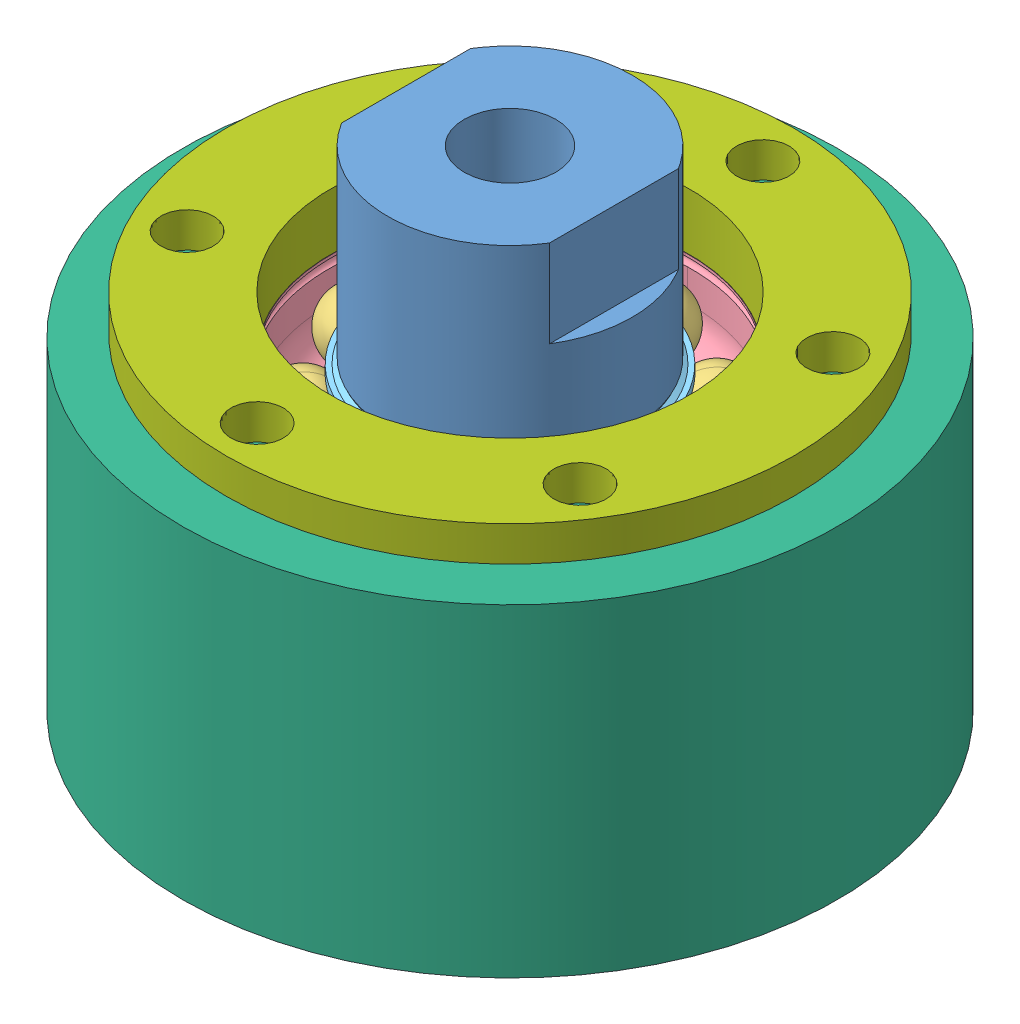
SolidWorks assembly Lagerblok, configuration Default. Lengths in mm.
Overall size (100.82 56 100.82).
23 component instances, 8 part files, 9 mates.
Components (placement in the parent):
- As-1: As [Default] at (-11.9686 24.4078 6.718) size (28 52 28)
- SKF_3204_ATN9-1: SKF_3204_ATN9 [Default] at (-11.9686 9.4078 6.718) x (0 -1 0) z (0.020105 0 0.999798) size (20.6 47 47)
  - SKF_3204_ATN9_3-1: SKF_3204_ATN9_3 [Default] x (1 0 0) z (0 -0.707107 0.707107) size (7.94 7.94 7.94)
  - SKF_3204_ATN9_3-2: SKF_3204_ATN9_3 [Default] x (1 0 0) z (0 -1 0) size (7.94 7.94 7.94)
  - SKF_3204_ATN9_3-3: SKF_3204_ATN9_3 [Default] x (1 0 0) z (0 -0.707107 -0.707107) size (7.94 7.94 7.94)
  - SKF_3204_ATN9_3-4: SKF_3204_ATN9_3 [Default] x (1 0 0) z (0 0 -1) size (7.94 7.94 7.94)
  - SKF_3204_ATN9_3-5: SKF_3204_ATN9_3 [Default] x (1 0 0) z (0 0.707107 -0.707107) size (7.94 7.94 7.94)
  - SKF_3204_ATN9_3-6: SKF_3204_ATN9_3 [Default] x (1 0 0) z (0 1 0) size (7.94 7.94 7.94)
  - SKF_3204_ATN9_3-7: SKF_3204_ATN9_3 [Default] x (1 0 0) z (0 0.707107 0.707107) size (7.94 7.94 7.94)
  - SKF_3204_ATN9_3-8: SKF_3204_ATN9_3 [Default] at origin size (7.94 7.94 7.94)
  - SKF_3204_ATN9_12-1: SKF_3204_ATN9_12 [Default] x (1 0 0) z (0 -0.707107 0.707107) size (7.94 7.94 7.94)
  - SKF_3204_ATN9_12-2: SKF_3204_ATN9_12 [Default] x (1 0 0) z (0 -1 0) size (7.94 7.94 7.94)
  - SKF_3204_ATN9_12-3: SKF_3204_ATN9_12 [Default] x (1 0 0) z (0 -0.707107 -0.707107) size (7.94 7.94 7.94)
  - SKF_3204_ATN9_12-4: SKF_3204_ATN9_12 [Default] x (1 0 0) z (0 0 -1) size (7.94 7.94 7.94)
  - SKF_3204_ATN9_12-5: SKF_3204_ATN9_12 [Default] x (1 0 0) z (0 0.707107 -0.707107) size (7.94 7.94 7.94)
  - SKF_3204_ATN9_12-6: SKF_3204_ATN9_12 [Default] x (1 0 0) z (0 1 0) size (7.94 7.94 7.94)
  - SKF_3204_ATN9_12-7: SKF_3204_ATN9_12 [Default] x (1 0 0) z (0 0.707107 0.707107) size (7.94 7.94 7.94)
  - SKF_3204_ATN9_12-8: SKF_3204_ATN9_12 [Default] at origin size (7.94 7.94 7.94)
  - SKF_3204_ATN9_21-1: SKF_3204_ATN9_21 [Default] at origin size (20.6 47 47)
  - SKF_3204_ATN9_23-1: SKF_3204_ATN9_23 [Default] at origin size (20.6 29.93 29.93)
- Lagerhuis-1: Lagerhuis [Default] at (-11.9686 -25.5922 6.718) x (0.452463 0 0.891783) z (-0.891783 0 0.452463) size (75 37 75)
- Klemring-1: Klemring [Default] at (-11.9686 11.9078 6.718) x (0.546075 0 -0.837736) z (0.837736 0 0.546075) size (65 6.5 65)
- SKF_KM_4-1: SKF_KM_4 [Default] at (-11.9686 -17.1922 6.718) x (0 1 0) z (-0.00568 0 -0.999984) size (7.1 31.88 31.88)
Mates (geometry in assembly coordinates):
- Concentric1: concentric anti-aligned: cylinder of As-1 through (-11.9686 -21.5922 6.718) axis (0 1 0) radius 10; cylinder of SKF_3204_ATN9-1/SKF_3204_ATN9_23-1 through (-11.9686 -11.1922 6.718) axis (0 -1 0) radius 10
- Coincident1: coincident anti-aligned: plane of As-1 through (-11.9686 9.4078 6.718) normal (0 -1 0); plane of SKF_3204_ATN9-1/SKF_3204_ATN9_23-1 through (2.9923 9.4078 6.4171) normal (0 1 0)
- Concentric3: concentric anti-aligned: cylinder of SKF_3204_ATN9-1/SKF_3204_ATN9_21-1 through (-11.9686 -0.8922 6.718) axis (0 -1 0) radius 23.5; cylinder of Lagerhuis-1 through (-11.9686 -11.1922 6.718) axis (0 1 0) radius 23.5
- Coincident4: coincident anti-aligned: plane of SKF_3204_ATN9-1/SKF_3204_ATN9_21-1 through (8.4773 -11.1922 6.3068) normal (0 -1 0); plane of Lagerhuis-1 through (-11.9686 -11.1922 6.718) normal (0 1 0)
- Concentric4: concentric aligned: cylinder of Lagerhuis-1 through (-11.9686 11.4078 6.718) axis (0 -1 0) radius 37.5; cylinder of Klemring-1 through (-11.9686 15.9078 6.718) axis (0 -1 0) radius 32.5
- Coincident5: coincident anti-aligned: plane of SKF_3204_ATN9-1/SKF_3204_ATN9_21-1 through (10.5269 9.4078 6.2656) normal (0 1 0); plane of Klemring-1 through (-11.9686 9.4078 6.718) normal (0 -1 0)
- Coincident6: coincident: line of ? through (-11.9686 0.8523 6.718) axis (0 -1 0); line of SKF_KM_4-1 through (-11.9686 -8.3558 6.718) axis (0 -1 0)
- Coincident7: coincident anti-aligned: plane of SKF_3204_ATN9-1/SKF_3204_ATN9_23-1 through (-0.9708 -11.1922 6.4968) normal (0 -1 0); plane of SKF_KM_4-1 through (-1.9688 -11.1922 6.6612) normal (0 1 0)
- Concentric5: concentric aligned: circle of Lagerhuis-1; cylinder of Klemring-1 through (-13.4549 9.4078 34.1778) axis (0 1 0) radius 3
